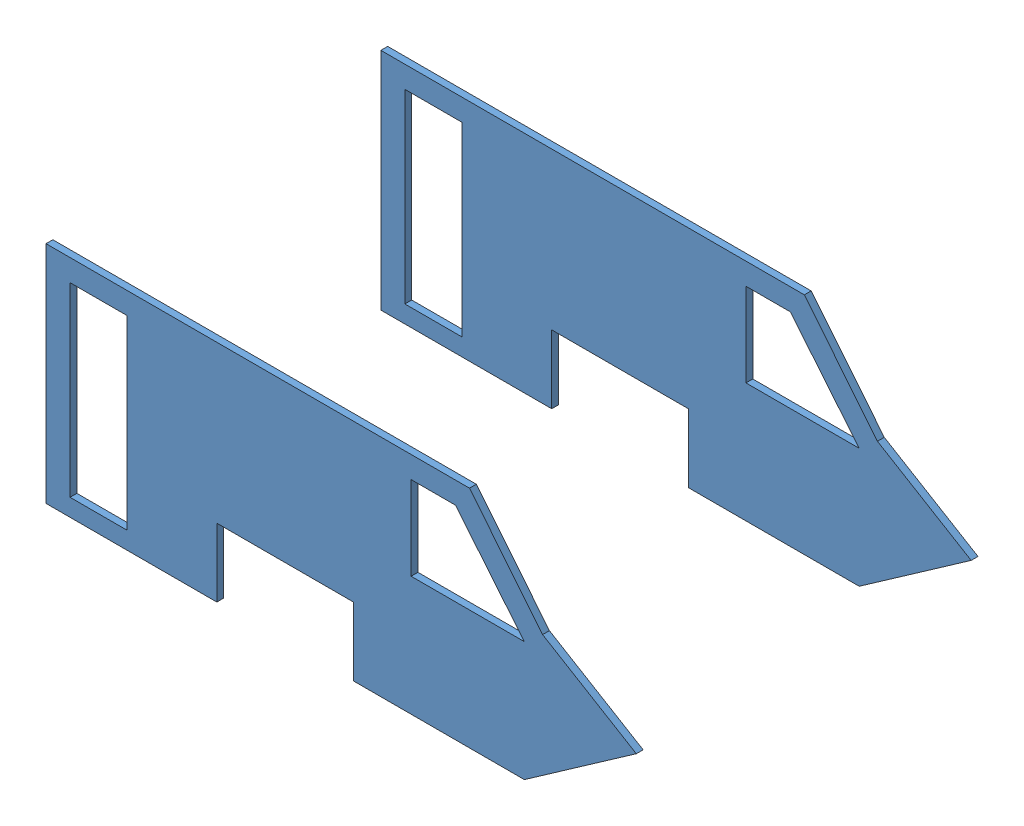
SolidWorks assembly Assemblage1, configuration Défaut. Lengths in mm.
Overall size (172.77 65.85 100).
2 component instances, 1 part files, 3 mates.
Components (placement in the parent):
- coté-1: coté [Défaut] at (-48.2979 -13.765 1) size (172.77 65.85 2)
- coté-2: coté [Défaut] at (-48.2979 -13.765 99) size (172.77 65.85 2)
Mates (geometry in assembly coordinates):
- Coïncidente1: coincident: plane of coté-1 through (-48.2979 52.0823 -1) normal (-1 0 0); plane of coté-2 through (-48.2979 52.0823 97) normal (-1 0 0)
- Coïncidente2: coincident: plane of coté-1 through (75.6419 52.0823 -1) normal (0 1 0); plane of coté-2 through (75.6419 52.0823 97) normal (0 1 0)
- Distance1: distance = 100 mm anti-aligned: plane of coté-1 through (-48.2979 -13.765 -1) normal (0 0 -1); plane of coté-2 through (-48.2979 -13.765 99) normal (0 0 1)
